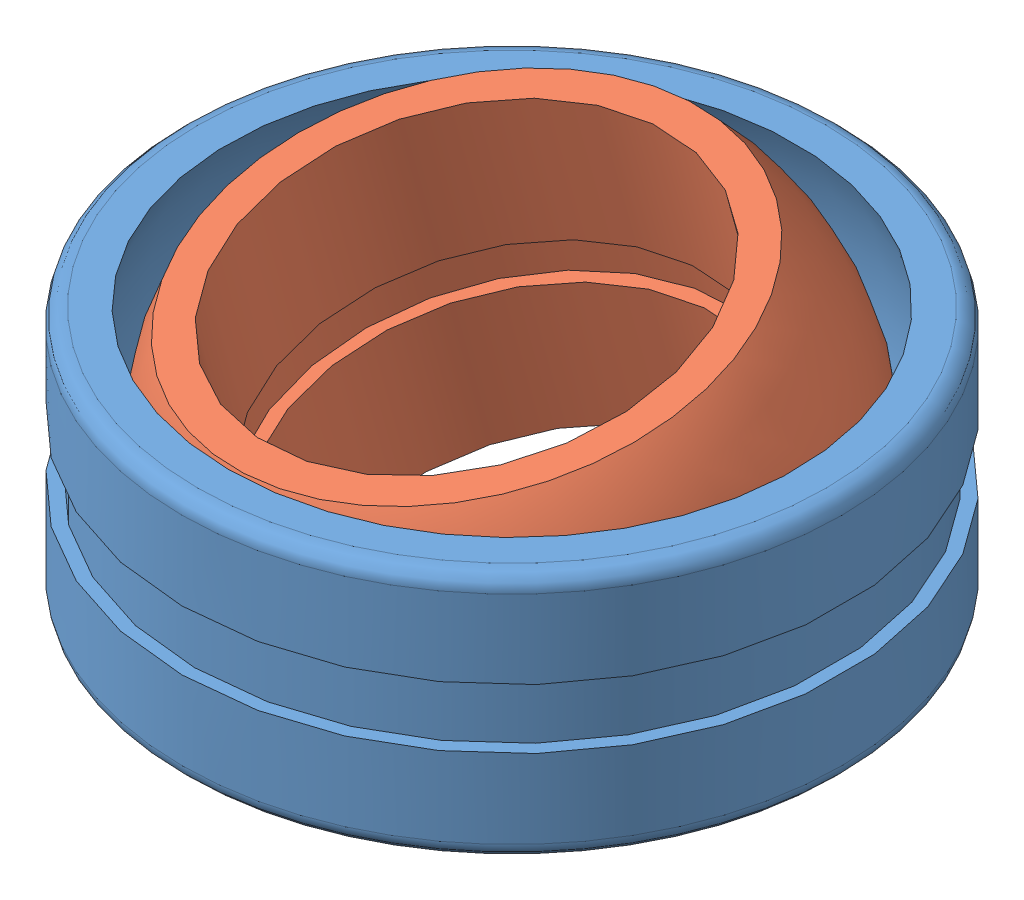
SolidWorks assembly GE25 ES-2RS, configuration По умолчанию. Lengths in mm.
Overall size (50 29.63 52.09).
2 component instances, 2 part files, 1 mates.
Components (placement in the parent):
- outer_ring-1: outer_ring [По умолчанию] at origin size (42 15.8 42)
- inner_ring-1: inner_ring [По умолчанию] x (0.823064 -0.070006 0.563618) z (-0.563834 -0.219965 0.796057) size (35.07 20 35.07)
Mates (geometry in assembly coordinates):
- Coincident4: coincident: point of inner_ring-1; point of assembly
